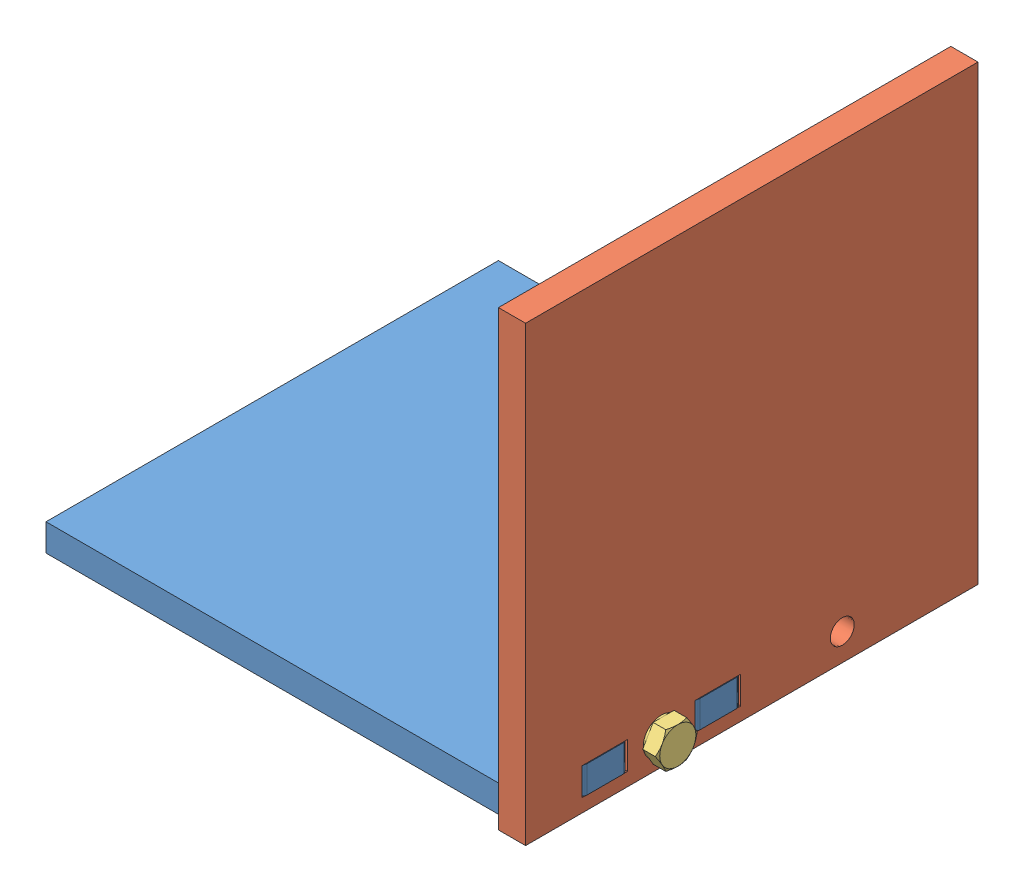
SolidWorks assembly Assem6, configuration Default. Lengths in mm.
Overall size (109.65 100 100).
4 component instances, 4 part files, 10 mates.
Components (placement in the parent):
- first^Assem6-1: first^Assem6 [Default] at origin size (106.1 6 100) (virtual)
- second^Assem6-4: second^Assem6 [Default] at (50 47 0) x (0 -1 0) z (0 0 1) size (100 6 100) (virtual)
- hex cap screw_am-4: hex cap screw_am [B18.2.3.1M - Hex cap screw, M5 x 0.8 x 30 --16N] at (59.65 3 20) x (-1 0 0) z (0 1 0) size (33.65 9.24 8)
- hex nut style 1_am-1: hex nut style 1_am [B18.2.4.1M - Hex nut, Style 1,  M5 x 0.8 --D-N] at (40.35 3 20) x (0 0 -1) z (1 0 0) size (8 9.24 4.7)
Mates (geometry in assembly coordinates):
- Coincident3: coincident anti-aligned: plane of first^Assem6-1 through (50 6 -50) normal (1 0 0); plane of second^Assem6-4 through (50 47 0) normal (-1 0 0)
- Coincident4: coincident aligned: plane of first^Assem6-1 through (-50 6 50) normal (0 0 1); plane of second^Assem6-4 through (56 97 50) normal (0 0 1)
- Concentric31: concentric aligned: cylinder of second^Assem6-4 through (56 3 30) axis (1 0 0) radius 2.65; cylinder of ? through (59.65 3 30) axis (1 0 0) radius 2.5
- Coincident71: coincident anti-aligned: plane of second^Assem6-4 through (56 47 0) normal (1 0 0); plane of ? through (56 6.7609 32.6812) normal (-1 0 0)
- Coincident81: coincident anti-aligned: plane of second^Assem6-4 through (56 47 0) normal (1 0 0); plane of hex cap screw_am-4 through (56 3 24.6188) normal (-1 0 0)
- Concentric7: concentric aligned: cylinder of second^Assem6-4 through (56 3 20) axis (1 0 0) radius 2.65; cylinder of hex cap screw_am-4 through (59.65 3 20) axis (1 0 0) radius 2.5
- Coincident14: coincident anti-aligned: plane of first^Assem6-1 through (0 3 0) normal (0 -1 0); plane of hex cap screw_am-4 through (59.65 3 20) normal (0 1 0)
- Concentric14: concentric aligned: cylinder of hex cap screw_am-4 through (59.65 3 20) axis (1 0 0) radius 2.5; cylinder of hex nut style 1_am-1 through (35.65 3 20) axis (1 0 0) radius 2.1
- Coincident19: coincident anti-aligned: plane of hex cap screw_am-4; plane of hex nut style 1_am-1 through (40.35 3 20) normal (0 0 -1)
- Width1: width anti-aligned: plane of first^Assem6-1 through (35.5 6 22.6) normal (1 0 0); plane of first^Assem6-1 through (40.5 6 24) normal (-1 0 0); plane of hex nut style 1_am-1 through (35.65 7.6188 20) normal (-1 0 0); plane of hex nut style 1_am-1 through (40.35 7.6188 20) normal (1 0 0)
